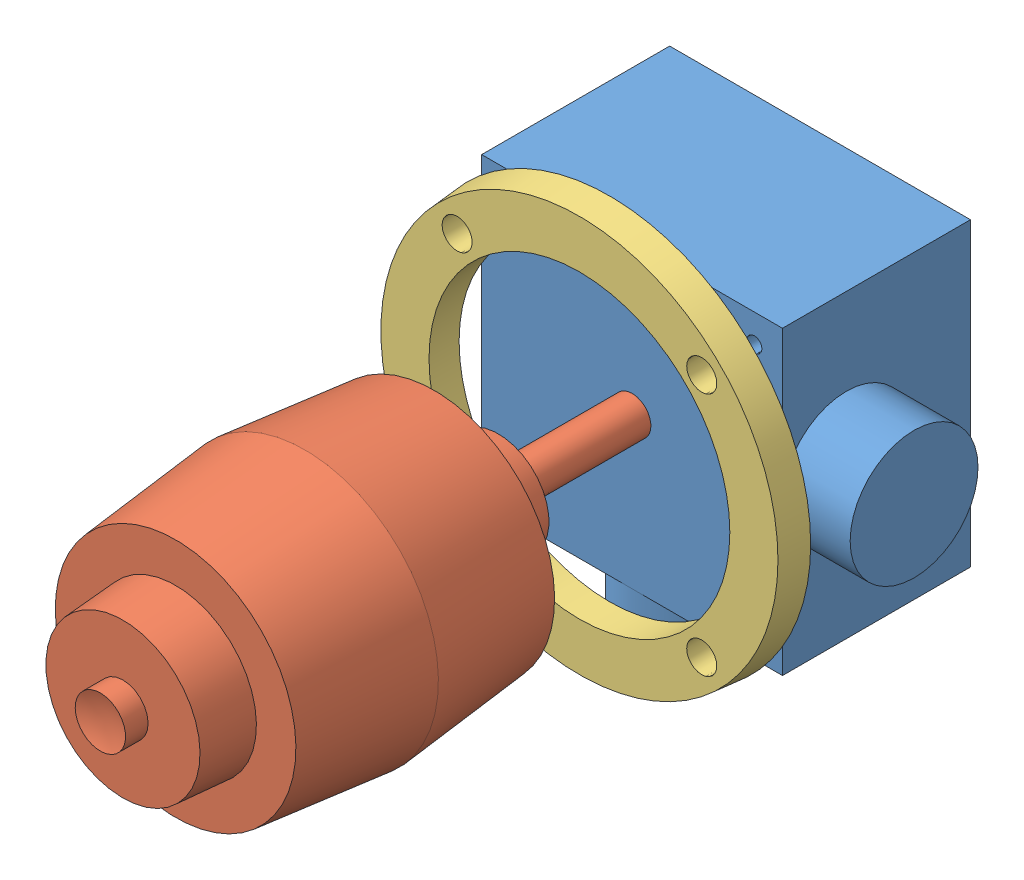
SolidWorks assembly JH-D400X-R4, configuration По умолчанию. Lengths in mm.
Overall size (55.75 55.75 95.7).
3 component instances, 3 part files, 7 mates.
Components (placement in the parent):
- JH-D400X-R4 part1-1: JH-D400X-R4 part1 [По умолчанию] at origin size (49 49 25)
- JH-D400X-R4 part2-1: JH-D400X-R4 part2 [По умолчанию] at (0 0 68.5) x (0.999788 0.020614 0) z (0.020614 -0.999788 0) size (35.5 84.2 35.5)
- JH-D400X-R4 part3-1: JH-D400X-R4 part3 [По умолчанию] at (0 0 28) x (0 -1 0) z (-1 0 0) size (53.5 4 53.5)
Mates (geometry in assembly coordinates):
- Coincident1: coordinate: point of StickBase-1
- Concentric1: concentric: cylinder of StickBase-1 through (0 -29 16.5) axis (0 1 0) radius 8.5; sphere of StickHandle-1
- Concentric2: concentric: cylinder of StickBase-1 through (29 0 16.5) axis (-1 0 0) radius 8.5; sphere of StickHandle-1
- LimitAngle3: limit planar angle = 0 rad anti-aligned: line of StickHandle-1 through (0 0 132.5065) axis (0 0 -1); line of StickBase-1 through (0 0 -25.5153) axis (0 0 1)
- Distance1: distance = 3 mm anti-aligned: plane of StickBase-1 through (0 0 25) normal (0 0 1); plane of StickRing-1 through (0 20 28) normal (0 0 -1)
- Concentric3: concentric anti-aligned: cylinder of StickBase-1 through (-16.2635 16.2635 15) axis (0 0 1) radius 1; cylinder of StickRing-1 through (-16.2635 16.2635 32) axis (0 0 -1) radius 2
- Concentric4: concentric anti-aligned: cylinder of StickBase-1 through (16.2635 -16.2635 15) axis (0 0 1) radius 1; cylinder of StickRing-1 through (16.2635 -16.2635 32) axis (0 0 -1) radius 2
